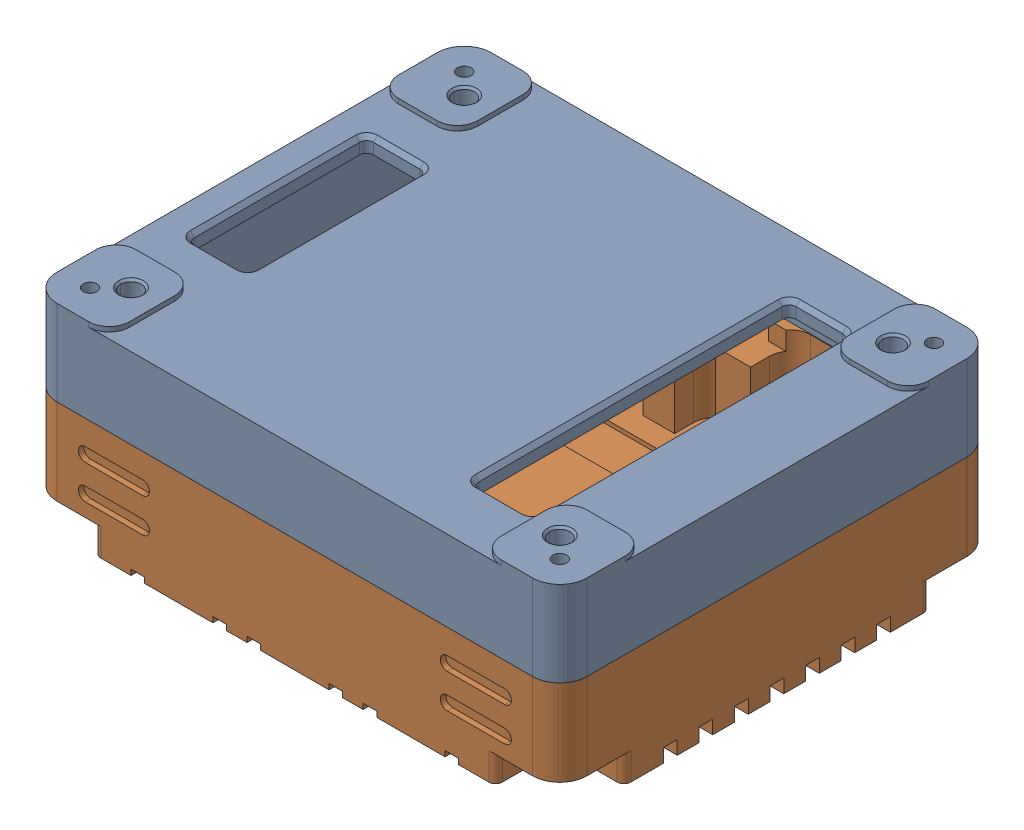
SolidWorks assembly PIXHAWK-5X-MUJU_ASM.stp, configuration Default. Lengths in mm.
Overall size (38.8 14.55 31.8).
2 component instances, 2 part files, 0 mates.
Components (placement in the parent):
- FMUV5X-DIKE-V13.stp-1: FMUV5X-DIKE-V13.stp [Default] at (0 4.25 0) x (1 0 0) z (0 -1 0) size (38.8 31.8 6.25)
- FMUV5X-SHANGGAI-V14.stp-1: FMUV5X-SHANGGAI-V14.stp [Default] at (0 -10.35 0) x (-1 0 0) z (0 1 0) size (38.8 31.8 10.35)
